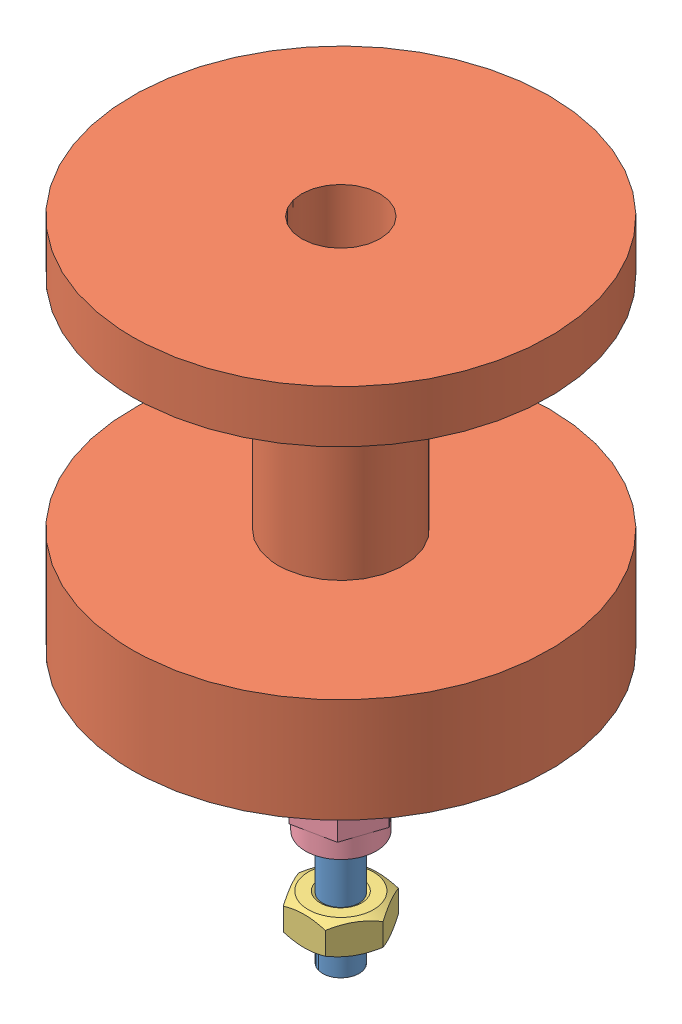
SolidWorks assembly 承重轮装配体_小型, configuration 默认. Lengths in mm.
Overall size (40 62 40).
5 component instances, 5 part files, 8 mates.
Components (placement in the parent):
- 半牙螺丝M4 45-1: 半牙螺丝M4 45 [默认] at (-7.0402 52.0271 -0.3574) size (7 49 7)
- 承重轮_小型-1: 承重轮_小型 [默认] at (-7.0402 58.0271 -0.3574) size (40 36 40)
- hex nuts, style 1-grades ab gb-1: hex nuts, style 1-grades ab gb [GB_FASTENER_NUT_SNAB1 M4-N] at (-7.0402 38.0271 -0.3574) x (1 0 0) z (0 1 0) size (8.08 7 3.2)
- 锁紧螺丝-1: 锁紧螺丝 [默认] at (-7.0402 48.0271 -0.3574) x (0.837169 0 0.546944) z (0.546944 0 -0.837169) size (7.58 5 7.59)
- 承重轮_01_01-1: 承重轮_01_01 [默认] at (-7.0402 58.0271 -0.3574) x (-0.837169 0 -0.546944) z (-0.546944 0 0.837169) size (12 10 12)
Mates (geometry in assembly coordinates):
- 重合1: coincident: plane of assembly; plane of assembly; plane of 半牙螺丝M4 45-1 through (-7.0402 77.0271 -0.3574) normal (0 -1 0); plane of 承重轮_小型-1 through (-7.0402 77.0271 -0.3574) normal (0 1 0)
- 同心2: concentric: cylinder of assembly; cylinder of assembly; cylinder of 半牙螺丝M4 45-1 through (-7.0402 32.0271 -0.3574) axis (0 1 0) radius 1.75; cylinder of hex nuts, style 1-grades ab gb-1 through (-7.0402 34.8271 -0.3574) axis (0 1 0) radius 1.621
- 同心3: concentric: cylinder of assembly; cylinder of assembly; cylinder of 半牙螺丝M4 45-1 through (-7.0402 32.0271 -0.3574) axis (0 1 0) radius 1.75; cylinder of 锁紧螺丝-1 through (-7.0402 43.0271 -0.3574) axis (0 1 0) radius 2
- 同心4: concentric: cylinder of assembly; cylinder of assembly; cylinder of 半牙螺丝M4 45-1 through (-7.0402 32.0271 -0.3574) axis (0 1 0) radius 1.75; cylinder of 承重轮_小型-1 through (-7.0402 105.0271 -0.3574) axis (0 -1 0) radius 2
- 距离1: distance = 5 mm: plane of assembly; plane of assembly; plane of 锁紧螺丝-1 through (-7.0402 43.0271 -0.3574) normal (0 -1 0); plane of hex nuts, style 1-grades ab gb-1 through (-2.9988 38.0271 -0.3574) normal (0 1 0)
- 重合3: coincident: plane of assembly; plane of assembly; plane of 承重轮_小型-1 through (-7.0402 58.0271 -0.3574) normal (0 -1 0); plane of 承重轮_01_01-1 through (-7.0402 58.0271 -0.3574) normal (0 1 0)
- 重合4: coincident: plane of assembly; plane of assembly; plane of 锁紧螺丝-1 through (-7.0402 48.0271 -0.3574) normal (0 1 0); plane of 承重轮_01_01-1 through (-7.0402 48.0271 -0.3574) normal (0 -1 0)
- 同心5: concentric: cylinder of assembly; cylinder of assembly; cylinder of 半牙螺丝M4 45-1 through (-7.0402 32.0271 -0.3574) axis (0 1 0) radius 1.75; cylinder of 承重轮_01_01-1 through (-7.0402 50.0271 -0.3574) axis (0 1 0) radius 4.5
